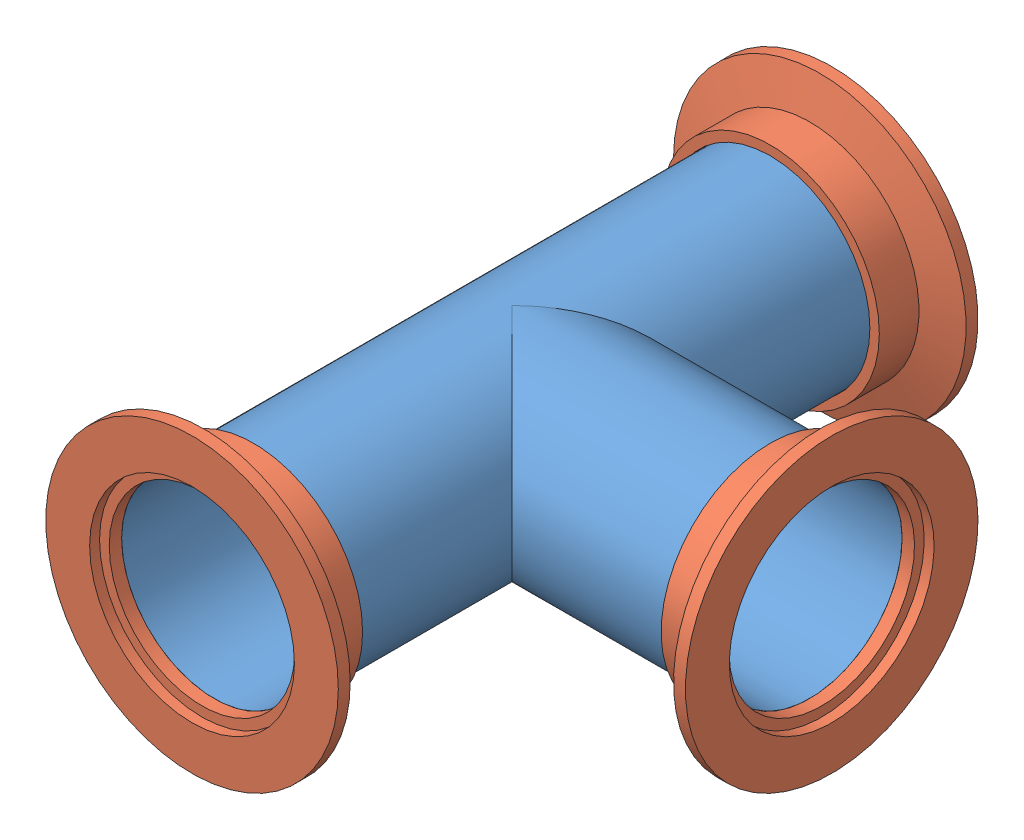
SolidWorks assembly 724003, configuration Default. Lengths in mm.
Overall size (119.38 97.86 163.83).
4 component instances, 2 part files, 6 mates.
Components (placement in the parent):
- 404503-1: 404503 [Default] at (37.092 86.8408 109.0559) size (101.6 50.8 152.4)
- 713004-1: 713004 [Default] at (37.092 86.8408 27.1409) x (0 0 1) z (-1 0 0) size (15.75 74.93 74.93)
- 713004-2: 713004 [Default] at (37.092 86.8408 190.9709) x (0 0 -1) z (1 0 0) size (15.75 74.93 74.93)
- 713004-3: 713004 [Default] at (119.007 86.8408 109.0559) x (-1 0 0) z (0 -0.924225 -0.381849) size (15.75 74.93 74.93)
Mates (geometry in assembly coordinates):
- Coincident1: coincident: plane of 404503-1 through (37.092 86.8408 185.2559) normal (0 0 1); plane of 713004-2 through (37.092 112.3678 185.2559) normal (0 0 -1)
- Coincident2: coincident: plane of 404503-1 through (113.292 86.8408 109.0559) normal (1 0 0); plane of 713004-3 through (113.292 96.5883 85.4632) normal (-1 0 0)
- Coincident3: coincident: plane of 404503-1 through (37.092 86.8408 32.8559) normal (0 0 -1); plane of 713004-1 through (37.092 112.3678 32.8559) normal (0 0 1)
- Concentric1: concentric anti-aligned: cylinder of 404503-1 through (37.092 86.8408 185.2559) axis (0 0 -1) radius 25.4; cylinder of 713004-2 through (37.092 86.8408 190.9709) axis (0 0 1) radius 27.94
- Concentric2: concentric aligned: cylinder of 404503-1 through (37.092 86.8408 185.2559) axis (0 0 -1) radius 25.4; cylinder of 713004-1 through (37.092 86.8408 27.1409) axis (0 0 -1) radius 27.94
- Concentric3: concentric anti-aligned: cylinder of 404503-1 through (113.292 86.8408 109.0559) axis (-1 0 0) radius 25.4; cylinder of 713004-3 through (119.007 86.8408 109.0559) axis (1 0 0) radius 27.94
